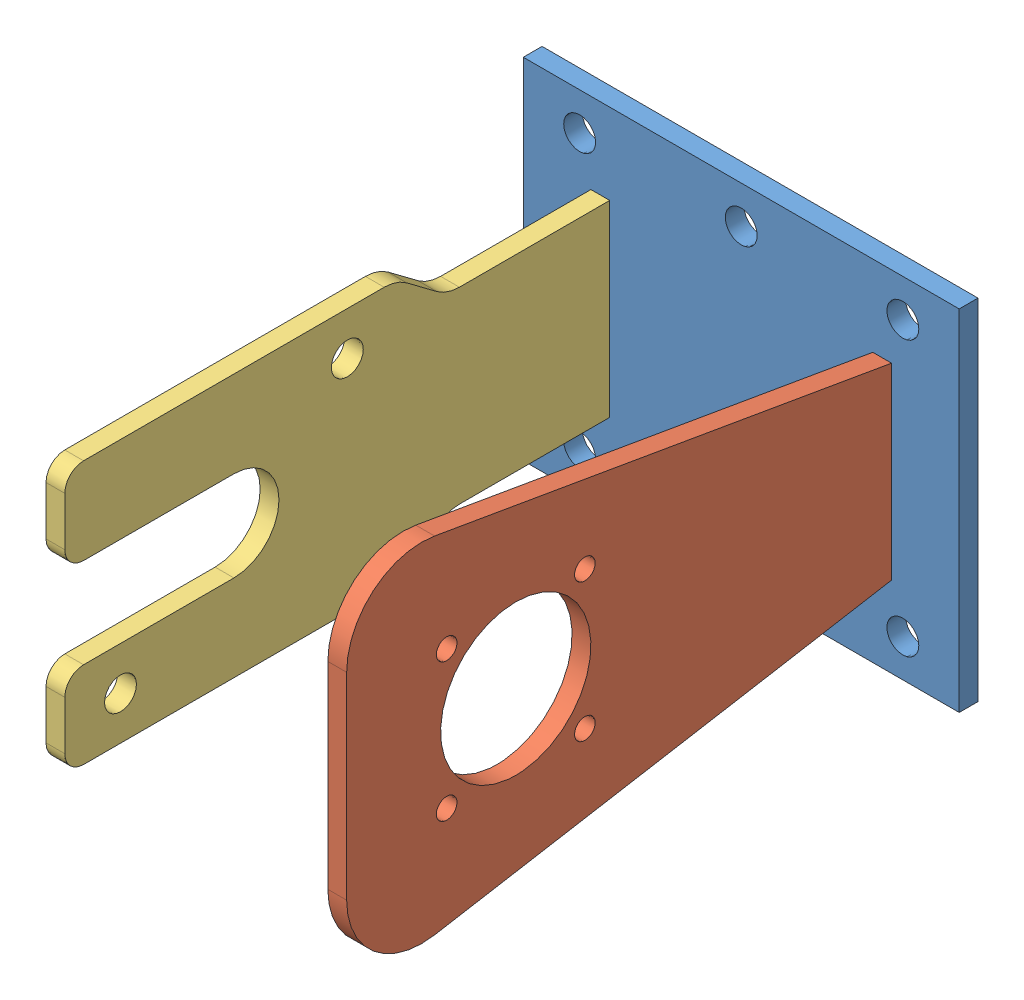
SolidWorks assembly Winch Bracket, configuration Default. Lengths in mm.
Overall size (116 93 150).
3 component instances, 3 part files, 7 mates.
Components (placement in the parent):
- Bottom Plate-1: Bottom Plate [Default] at origin size (116 93 5)
- Side Plate Motor-1: Side Plate Motor [Default] at (40 0 5) x (0 -1 0) z (-1 0 0) size (92.51 145 5)
- Side Plate Bearing-1: Side Plate Bearing [Default] at (-35 0 5) x (0 -1 0) z (-1 0 0) size (70 145 5)
Mates (geometry in assembly coordinates):
- Coincident1: coordinate: point of Bottom Plate-1
- Coincident2: coincident anti-aligned: plane of Bottom Plate-1 through (0 0 5) normal (0 0 1); plane of Side Plate Motor-1 through (35 -25 5) normal (0 0 -1)
- Distance1: distance = 35 mm anti-aligned: plane of Side Plate Motor-1 through (35 0 5) normal (-1 0 0)
- Coincident4: coincident anti-aligned: plane of Bottom Plate-1 through (0 0 0) normal (0 1 0); plane of Side Plate Motor-1 through (40 0 5) normal (0 -1 0)
- Coincident5: coincident anti-aligned: plane of Bottom Plate-1 through (0 0 5) normal (0 0 1); plane of Side Plate Bearing-1 through (-40 -25 5) normal (0 0 -1)
- Coincident6: coincident anti-aligned: plane of Side Plate Bearing-1 through (-35 0 5) normal (0 -1 0)
- Distance2: distance = 35 mm aligned: plane of Side Plate Bearing-1 through (-35 0 105) normal (1 0 0)
